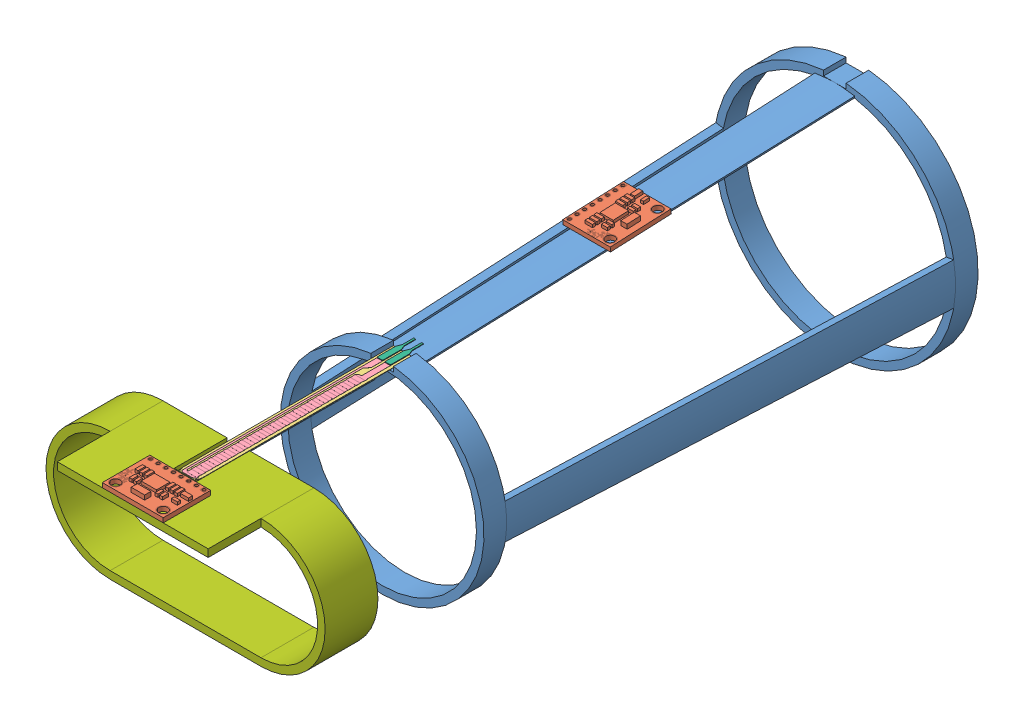
SolidWorks assembly Assmbly, configuration Default. Lengths in mm.
Overall size (93.98 81.1 243.99).
12 component instances, 7 part files, 12 mates.
Components (placement in the parent):
- upperbrace-1: upperbrace [Default] at (77.9421 104.445 98.9946) size (81.28 81.1 160.02)
- MPU_6050.step-1: MPU_6050.step [Default] at (77.9421 141.4635 176.1736) x (0 -0.043818 0.99904) z (0 0.99904 0.043818) size (20.5 16 3)
  - pcb.step-1: pcb.step [Default] at origin size (20.5 16 3)
- FlexSensor-1: FlexSensor [Default] at (27.6938 123.9314 301.8648) x (-1 0 0) z (0 0 -1) size (6.35 0.65 79.26)
  - PlasticFilm-1: PlasticFilm [Default] at (-52.7883 12.8986 54.2802) size (6.35 0.13 73.81)
  - Flex_Sensor_Circuit-1: Flex_Sensor_Circuit [Default] at origin size (4.83 0.04 72.39)
  - Plastic_Stiffner-1: Plastic_Stiffner [Default] at (-52.7883 12.8986 54.2802) x (-1 0 0) z (0 -1 0) size (6.35 61.29 0.3)
  - GoldProngTerminal-1: GoldProngTerminal [Default] at (0 13.0383 0) x (1 0 0) z (0 1 0) size (1.9 11.8 0.2)
  - GoldProngTerminal-2: GoldProngTerminal [Default] at (-2.667 13.0383 0) x (1 0 0) z (0 1 0) size (1.9 11.8 0.2)
- palmBrace-1: palmBrace [Default] at (77.9421 116.51 312.507) x (-1 0 0) z (0 0 -1) size (93.98 43.18 35.56)
- MPU_6050.step-2: MPU_6050.step [Default] at (77.9421 139.6 331.177) x (-1 0 0) z (0 1 0) size (20.5 16 3)
  - pcb.step-1: pcb.step [Default] at origin size (20.5 16 3)
Mates (geometry in assembly coordinates):
- Tangent1: tangent anti-aligned: cone of upperbrace-1 through (77.9421 104.445 102.8046) axis (0 0 1); plane of MPU_6050.step-1/pcb.step-1 through (77.9421 139.9649 176.1079) normal (0 -0.99904 -0.043818)
- Tangent2: tangent anti-aligned: cone of upperbrace-1 through (77.9421 104.445 102.8046) axis (0 0 1); plane of MPU_6050.step-1/pcb.step-1 through (77.9421 139.9649 176.1079) normal (0 -0.99904 -0.043818)
- Width2: width anti-aligned: plane of upperbrace-1 through (77.9421 104.445 98.9946) normal (-0.984808 -0.173648 0); plane of MPU_6050.step-1/pcb.step-1 through (77.9421 104.445 98.9946) normal (0.984808 -0.173648 0); plane of upperbrace-1 through (69.9421 141.0143 186.4138) normal (-1 0 0); plane of MPU_6050.step-1/pcb.step-1 through (85.9421 141.9126 165.9334) normal (1 0 0)
- Coincident2: coincident anti-aligned: plane of upperbrace-1 through (74.1321 136.83 95.1836) normal (0 1 0); plane of FlexSensor-1/PlasticFilm-1 through (77.3071 136.83 318.222) normal (0 -1 0)
- Coincident3: coincident anti-aligned: plane of upperbrace-1 through (74.1321 136.83 95.1836) normal (1 0 0); plane of FlexSensor-1/PlasticFilm-1 through (74.1321 136.957 247.5846) normal (-1 0 0)
- Coincident4: coincident aligned: plane of upperbrace-1 through (77.9421 104.445 247.5846) normal (0 0 -1); plane of FlexSensor-1/PlasticFilm-1 through (80.4821 136.957 247.5846) normal (0 0 -1)
- Coincident5: coincident anti-aligned: plane of FlexSensor-1/PlasticFilm-1 through (77.3071 136.83 318.222) normal (0 -1 0); plane of palmBrace-1 through (81.7521 136.83 303.616) normal (0 1 0)
- Coincident6: coincident aligned: plane of upperbrace-1 through (81.7521 136.83 95.1836) normal (-1 0 0); plane of palmBrace-1 through (81.7521 136.83 303.616) normal (-1 0 0)
- Tangent3: tangent anti-aligned: cylinder of FlexSensor-1/PlasticFilm-1 through (77.3071 136.957 318.222) axis (0 -1 0) radius 3.175; plane of palmBrace-1 through (77.9421 116.51 321.397) normal (0 0 -1)
- Coincident7: coincident: plane of palmBrace-1 through (103.3421 138.1 303.617) normal (0 1 0); plane of MPU_6050.step-2/pcb.step-1 through (77.9421 138.1 331.177) normal (0 -1 0)
- Coincident8: coincident: plane of palmBrace-1 through (77.9421 116.51 339.177) normal (0 0 1); plane of MPU_6050.step-2/pcb.step-1 through (88.1921 139.6 339.177) normal (0 0 1)
- Width3: width anti-aligned: plane of MPU_6050.step-2/pcb.step-1 through (88.1921 139.6 323.177) normal (1 0 0); plane of palmBrace-1 through (67.6921 139.6 339.177) normal (-1 0 0); plane of MPU_6050.step-2/pcb.step-1 through (52.5421 138.1 339.177) normal (-1 0 0); plane of palmBrace-1 through (103.3421 138.1 339.177) normal (1 0 0)
